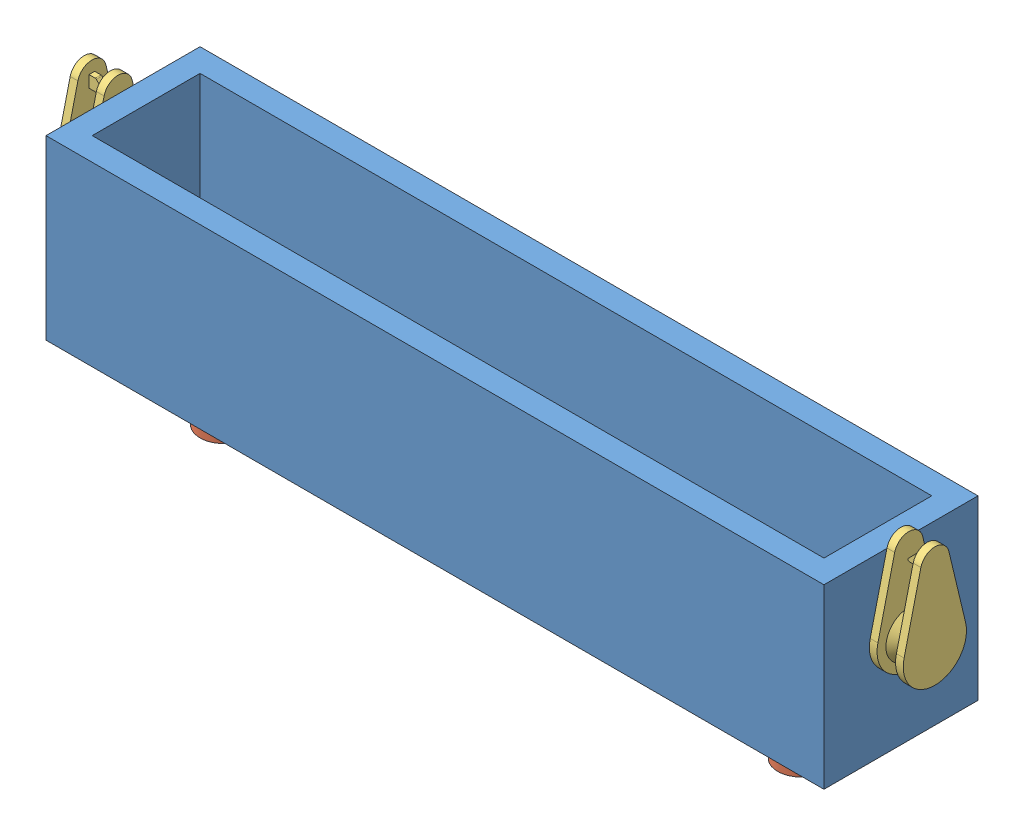
SolidWorks assembly 出绳点链接板-体, configuration 默认. Lengths in mm.
Overall size (110.44 32.48 49).
5 component instances, 3 part files, 7 mates.
Components (placement in the parent):
- 出绳点链接板-1: 出绳点链接板 [默认] at (-40.3436 16.0495 0) size (101 23 20)
- 柱塞螺丝M6-1: 柱塞螺丝M6 [默认] at (-77.8436 22.7895 0) x (-0.70895 0 -0.705258) z (-0.705258 0 0.70895) size (12 14.74 12)
- 柱塞螺丝M6-2: 柱塞螺丝M6 [默认] at (-2.8436 22.7895 0) x (-0.013162 0 -0.999913) z (-0.999913 0 0.013162) size (12 14.74 12)
- 零件1^latest1-1: 零件1^latest1 [默认] at (-95.8853 -106.9505 24.5) x (0 0 -1) z (1 0 0) size (28.6 15.58 4.4)
- 零件1^latest1-2: 零件1^latest1 [默认] at (14.5564 -106.9505 -24.5) x (0 0 1) z (-1 0 0) size (28.6 15.58 4.4)
Mates (geometry in assembly coordinates):
- 同心1: concentric anti-aligned: cylinder of 出绳点链接板-1 through (-77.8436 19.0495 0) axis (0 -1 0) radius 4; cylinder of 柱塞螺丝M6-1 through (-77.8436 16.0495 0) axis (0 1 0) radius 4
- 同心2: concentric anti-aligned: cylinder of 出绳点链接板-1 through (-2.8436 19.0495 0) axis (0 -1 0) radius 4; cylinder of 柱塞螺丝M6-2 through (-2.8436 16.0495 0) axis (0 1 0) radius 4
- 同心3: concentric anti-aligned: circle of 出绳点链接板-1; circle of 零件1^latest1-1
- 同心6: concentric anti-aligned: circle of 出绳点链接板-1; circle of 零件1^latest1-2
- 重合1: coincident anti-aligned: plane of 出绳点链接板-1 through (10.1564 19.0495 0) normal (1 0 0); plane of 零件1^latest1-2 through (10.1564 29.0495 0) normal (-1 0 0)
- 重合2: coincident aligned: plane of 出绳点链接板-1 through (-40.3436 16.0495 0) normal (0 -1 0); plane of 柱塞螺丝M6-1 through (-77.8436 16.0495 0) normal (0 -1 0)
- 重合3: coincident anti-aligned: plane of 出绳点链接板-1 through (-40.3436 19.0495 0) normal (0 1 0); plane of 柱塞螺丝M6-2 through (-2.8436 19.0495 0) normal (0 -1 0)
